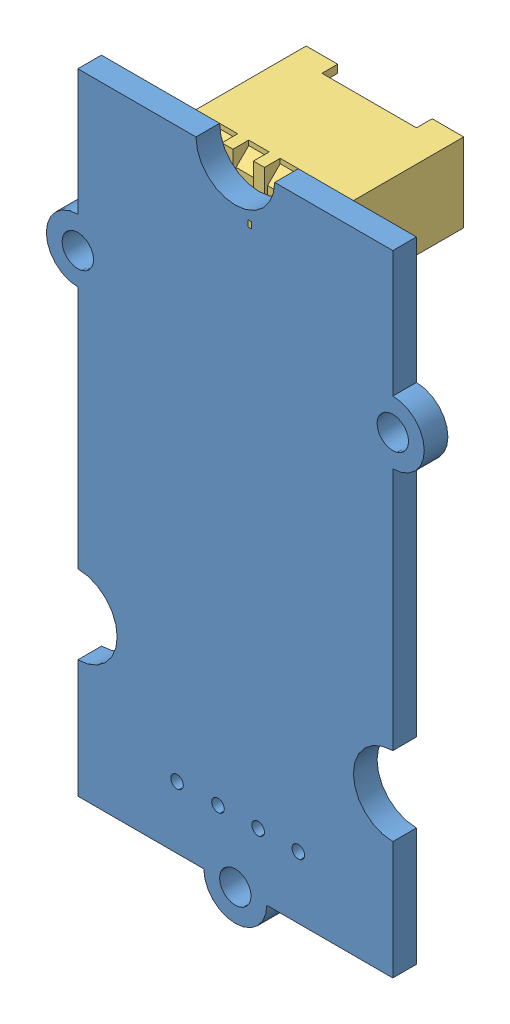
SolidWorks assembly Grove IMU - droit, configuration Défaut. Lengths in mm.
Overall size (24 42 9.5).
3 component instances, 3 part files, 4 mates.
Components (placement in the parent):
- Grove IMU Board-1: Grove IMU Board [Défaut] at (-2.3952 -22.0212 41.25) size (24 42 1.5)
- MPU9150-1: MPU9150 [Défaut] at (-3.0078 -7.8003 40.45) size (4 4 0.8)
- Connecteur Grove - droit-1: Connecteur Grove - droit [Défaut] at (-2.3952 11.9788 41.25) x (-1 0 0) z (0 -1 0) size (10 11 5)
Mates (geometry in assembly coordinates):
- Coïncidente2: coincident anti-aligned: plane of Grove IMU Board-1 through (-12.3952 -12.0212 41.25) normal (0 0 -1); plane of MPU9150-1 through (-3.0078 -7.8003 41.25) normal (0 0 1)
- Coïncidente3: coincident anti-aligned: plane of Grove IMU Board-1 through (-12.3952 -12.0212 41.25) normal (0 0 -1); plane of Connecteur Grove - droit-1 through (-2.3952 11.9788 41.25) normal (0 0 1)
- Distance1: distance = 1 mm aligned: plane of Connecteur Grove - droit-1 through (2.6048 16.9788 33.25) normal (0 1 0); plane of Grove IMU Board-1 through (-12.3952 17.9788 42.75) normal (0 1 0)
- Distance2: distance = 5 mm aligned: plane of Connecteur Grove - droit-1 through (2.6048 11.9788 33.25) normal (1 0 0); plane of Grove IMU Board-1 through (7.6048 17.9788 42.75) normal (1 0 0)
